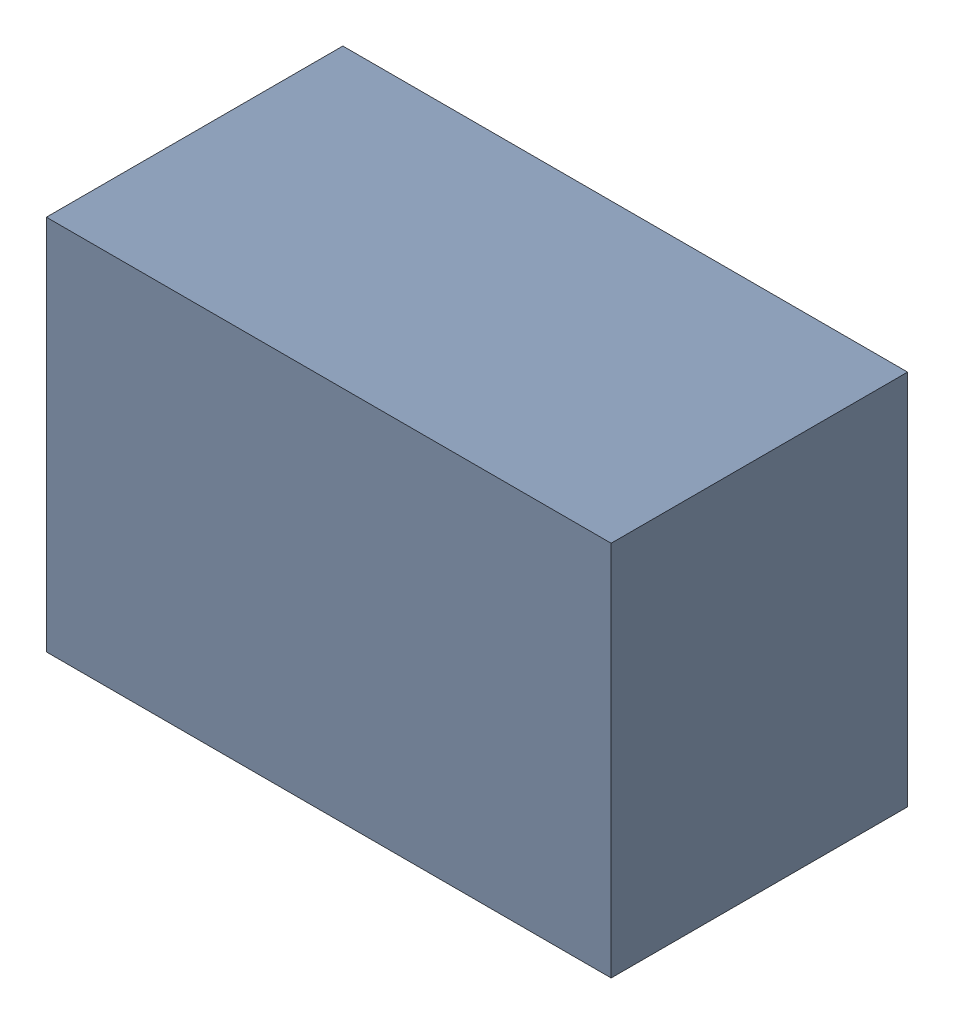
SolidWorks assembly USB23_L1, configuration Default. Lengths in mm.
Overall size (2.29 1.52 1.2).
2 component instances, 1 part files, 0 mates.
Components (placement in the parent):
- 402659088-1: 402659088 [Default] at (158.75 61.595 0) size (2.29 1.52 1.2)
  - Extruded_28-1: Extruded_28 [Default] at origin size (2.29 1.52 1.2)
